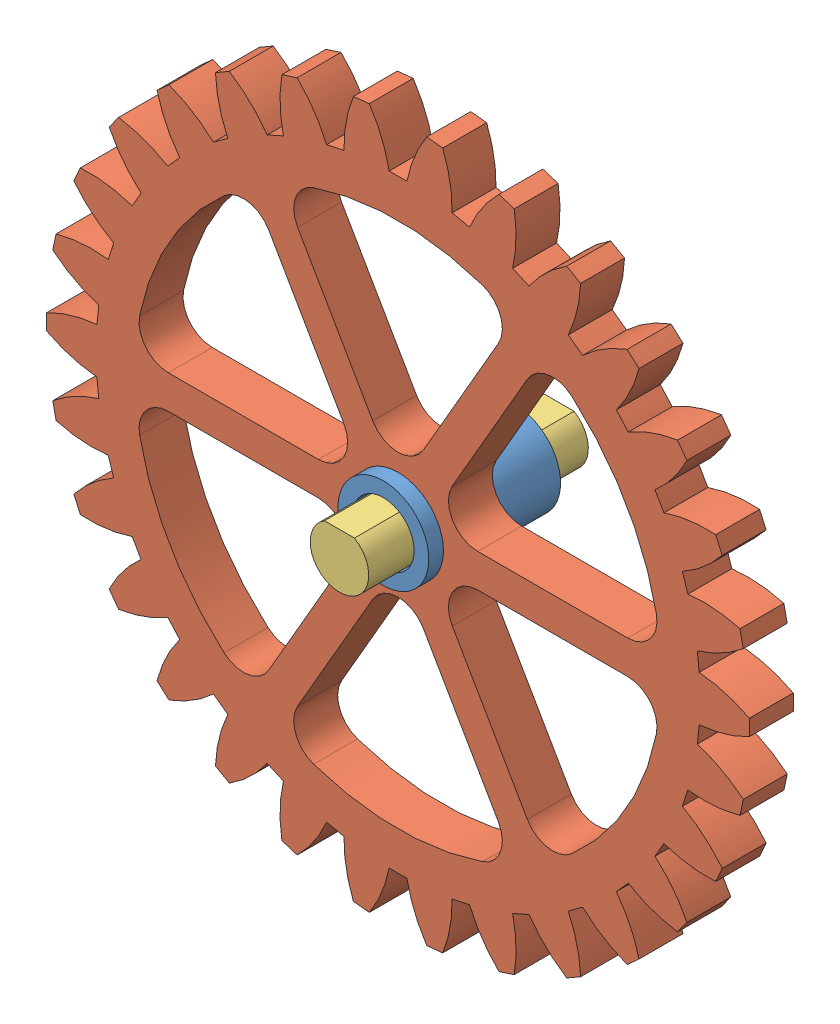
SolidWorks assembly Assem3, configuration Default. Lengths in mm.
Overall size (48 47.84 15).
4 component instances, 3 part files, 6 mates.
Components (placement in the parent):
- spacer-1: spacer [4.2mm ID 1L] at (10.9723 11.4982 24.4305) x (0.97362 0.228174 0) z (0 0 1) size (6.2 6.2 1)
- spacer-2: spacer [4.2mm ID 5L] at (10.9723 11.4982 16.4305) x (0.545669 0.838001 0) z (0 0 1) size (6.2 6.2 5)
- root_gear-1: root_gear [30T 1.5Mod] at (10.9723 11.4982 21.4305) size (48 47.84 3)
- axle-2: axle [15mm] at (10.9723 11.4982 13.4305) size (4 3.72 15)
Mates (geometry in assembly coordinates):
- Coincident2: coincident anti-aligned: plane of spacer-1 through (10.9723 11.4982 24.4305) normal (0 0 -1); plane of root_gear-1 through (10.9723 11.4982 24.4305) normal (0 0 1)
- Coincident3: coincident anti-aligned: plane of spacer-2 through (10.9723 11.4982 21.4305) normal (0 0 1); plane of root_gear-1 through (10.9723 11.4982 21.4305) normal (0 0 -1)
- Concentric1: concentric aligned: cylinder of spacer-1 through (10.9723 11.4982 25.4305) axis (0 0 -1) radius 2.1; cylinder of axle-2 through (10.9723 11.4982 28.4305) axis (0 0 -1) radius 2
- Concentric2: concentric aligned: cylinder of spacer-2 through (10.9723 11.4982 21.4305) axis (0 0 -1) radius 2.1; cylinder of axle-2 through (10.9723 11.4982 28.4305) axis (0 0 -1) radius 2
- Concentric3: concentric aligned: cylinder of root_gear-1 through (10.9723 11.4982 24.4305) axis (0 0 -1) radius 2; cylinder of axle-2 through (10.9723 11.4982 28.4305) axis (0 0 -1) radius 2
- Distance1: distance = 3 mm aligned: plane of axle-2 through (10.9723 11.4982 28.4305) normal (0 0 1); plane of spacer-1 through (10.9723 11.4982 25.4305) normal (0 0 1)
